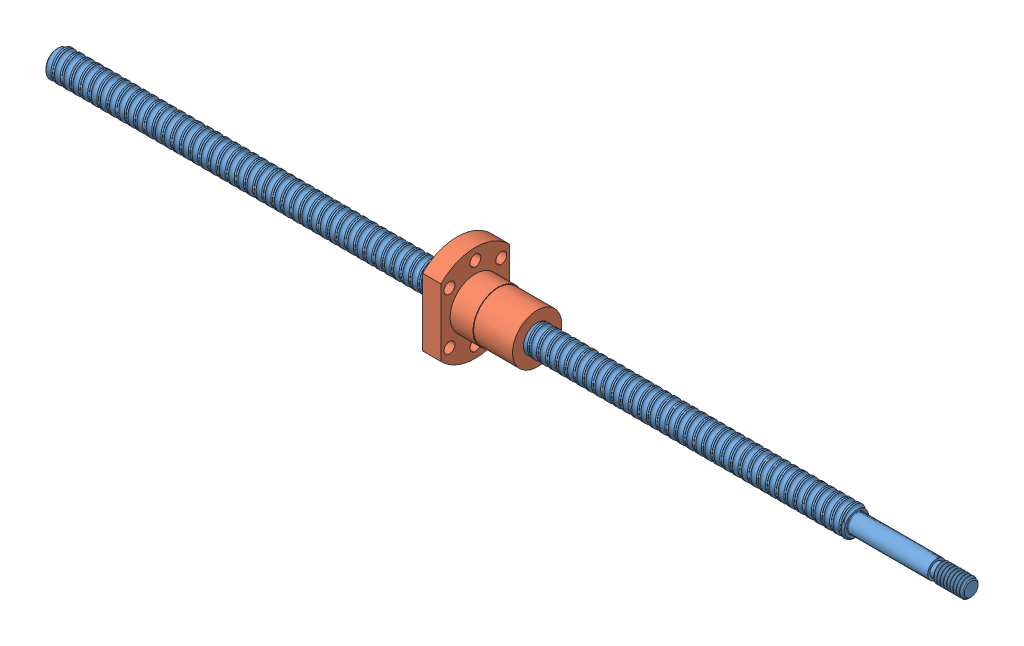
SolidWorks assembly Eustathios Ball Screw, configuration Default. Lengths in mm.
Overall size (403.49 42 30).
2 component instances, 2 part files, 3 mates.
Components (placement in the parent):
- Ballscrew to Replace Misumi in Erics Eustathios 1.5-1: Ballscrew to Replace Misumi in Erics Eustathios 1.5 [Default] at origin size (403.49 12.31 12.15)
- Golmart_BallScrew_Nut-1: Golmart_BallScrew_Nut [Default] at (185.5 0 0) x (0 0 1) z (0 -1 0) size (30 35 42)
Mates (geometry in assembly coordinates):
- Concentric1: concentric anti-aligned: cylinder of Ballscrew to Replace Misumi in Erics Eustathios 1.5-1 through (402 0 0) axis (-1 0 0) radius 6; cylinder of Golmart_BallScrew_Nut-1 through (177.5 0 0) axis (1 0 0) radius 6
- Parallel1: parallel aligned: plane of Golmart_BallScrew_Nut-1 through (177.5 14.6969 15) normal (0 0 1); plane of assembly through (0 0 0) normal (0 0 1)
- Symmetric1: symmetric aligned: plane of Ballscrew to Replace Misumi in Erics Eustathios 1.5-1 through (3 0 0) normal (-1 0 0); plane of Ballscrew to Replace Misumi in Erics Eustathios 1.5-1 through (352 6 0) normal (1 0 0); plane of Golmart_BallScrew_Nut-1 through (177.5 0 0) normal (-1 0 0)
